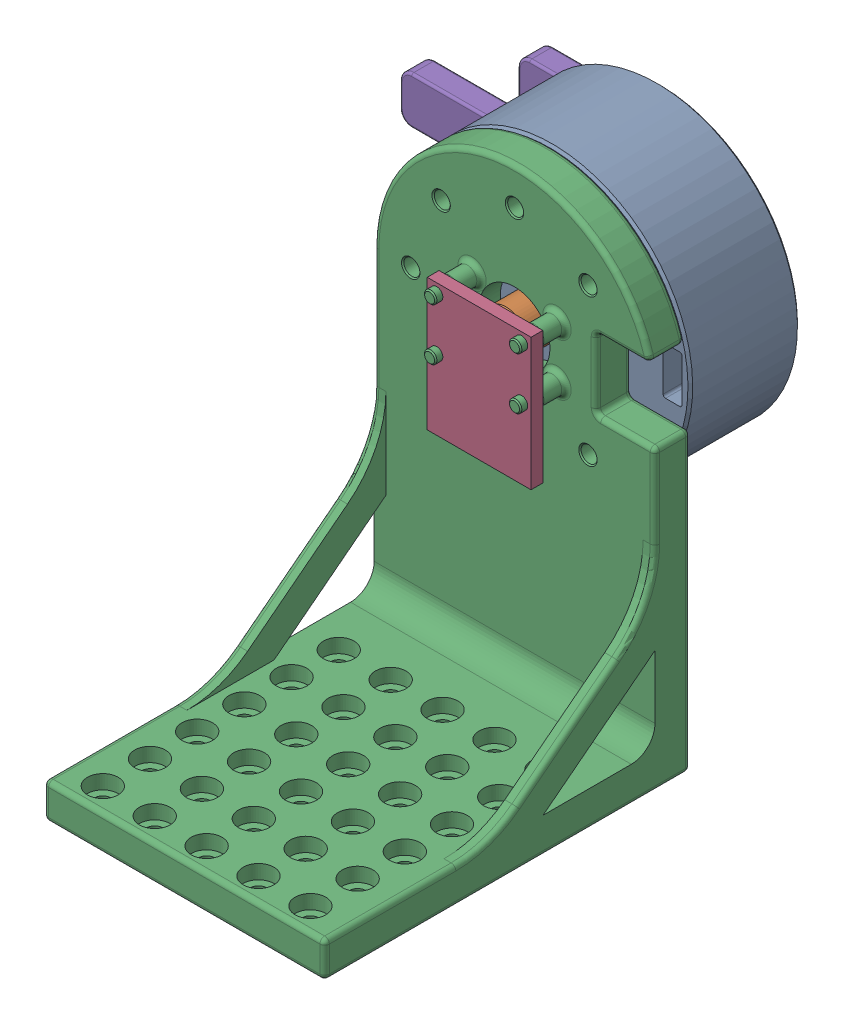
SolidWorks assembly GM5208__ENCODER_ASM, configuration Default. Lengths in mm.
Overall size (97.07 112.32 105.7).
5 component instances, 5 part files, 13 mates.
Components (placement in the parent):
- GM5208-24_PART-1: GM5208-24_PART [Default] at (0 20.25 0) x (-0.707107 0.707107 0) z (-0.707107 -0.707107 0) size (59.5 23.2 59.5)
- GM5208_ROTOR_MAGNET_ADAPTER-1: GM5208_ROTOR_MAGNET_ADAPTER [Default] at (0 20.25 -23.2) x (-1 0 0) z (0 -1 0) size (40 38 10)
- GM5208_STATOR_ENCODER_ADAPTER-1: GM5208_STATOR_ENCODER_ADAPTER [Default] at origin size (59.5 100 77.5)
- encoder_board-1: encoder_board [Default] at (0 20.25 15) x (-1 0 0) z (0 -1 0) size (22 4.5 28)
- GM5208_TUNINGFORK-1: GM5208_TUNINGFORK [Default] at (0 20.25 -23.2) x (0 -1 0) z (1 0 0) size (40 5 62.5)
Mates (geometry in assembly coordinates):
- Coincident2: coincident anti-aligned: plane of GM5208-24_PART-1 through (0 20.25 -23.2) normal (0 0 -1); plane of GM5208_ROTOR_MAGNET_ADAPTER-1 through (15 20.25 -23.2) normal (0 0 1)
- Concentric2: concentric aligned: cylinder of GM5208-24_PART-1 through (15 20.25 -23.2) axis (0 0 -1) radius 1.25; cylinder of GM5208_ROTOR_MAGNET_ADAPTER-1 through (15 20.25 -28.2) axis (0 0 -1) radius 1.7
- Concentric5: concentric aligned: cylinder of GM5208-24_PART-1 through (0 20.25 -16.135) axis (0 0 1) radius 4.75; cylinder of GM5208_STATOR_ENCODER_ADAPTER-1 through (0 20.25 -21.2132) axis (0 0 1) radius 7.5
- Coincident3: coordinate: point of GM5208_STATOR_ENCODER_ADAPTER-1
- Concentric6: concentric aligned: cylinder of GM5208-24_PART-1 through (15.5563 35.8063 0) axis (0 0 1) radius 1.25; cylinder of GM5208_STATOR_ENCODER_ADAPTER-1 through (15.5563 35.8063 7.5) axis (0 0 1) radius 1.7
- Coincident4: coincident anti-aligned: plane of GM5208-24_PART-1 through (0 20.25 0) normal (0 0 1); plane of GM5208_STATOR_ENCODER_ADAPTER-1 through (0 0 0) normal (0 0 -1)
- Concentric9: concentric aligned: cylinder of GM5208_STATOR_ENCODER_ADAPTER-1 through (-9 14.75 16.5) axis (0 0 -1) radius 1.3; cylinder of encoder_board-1 through (-9 14.75 12.5) axis (0 0 -1) radius 1.3
- Concentric10: concentric aligned: cylinder of GM5208_STATOR_ENCODER_ADAPTER-1 through (9 25.75 16.5) axis (0 0 -1) radius 1.3; cylinder of encoder_board-1 through (9 25.75 12.5) axis (0 0 -1) radius 1.3
- Coincident6: coincident anti-aligned: plane of GM5208_STATOR_ENCODER_ADAPTER-1 through (9 25.75 12.5) normal (0 0 1); plane of encoder_board-1 through (0 20.25 12.5) normal (0 0 -1)
- Concentric11: concentric aligned: circle of GM5208_ROTOR_MAGNET_ADAPTER-1; circle of encoder_board-1
- Concentric12: concentric aligned: cylinder of GM5208-24_PART-1 through (0 5.25 -23.2) axis (0 0 -1) radius 1.25; cylinder of GM5208_TUNINGFORK-1 through (0 5.25 -28.2) axis (0 0 -1) radius 1.7
- Concentric15: concentric aligned: cylinder of GM5208-24_PART-1 through (0 35.25 -23.2) axis (0 0 -1) radius 1.25; cylinder of GM5208_TUNINGFORK-1 through (0 35.25 -28.2) axis (0 0 -1) radius 1.7
- Coincident7: coincident anti-aligned: plane of GM5208-24_PART-1 through (0 20.25 -23.2) normal (0 0 -1); plane of GM5208_TUNINGFORK-1 through (0 20.25 -23.2) normal (0 0 1)
